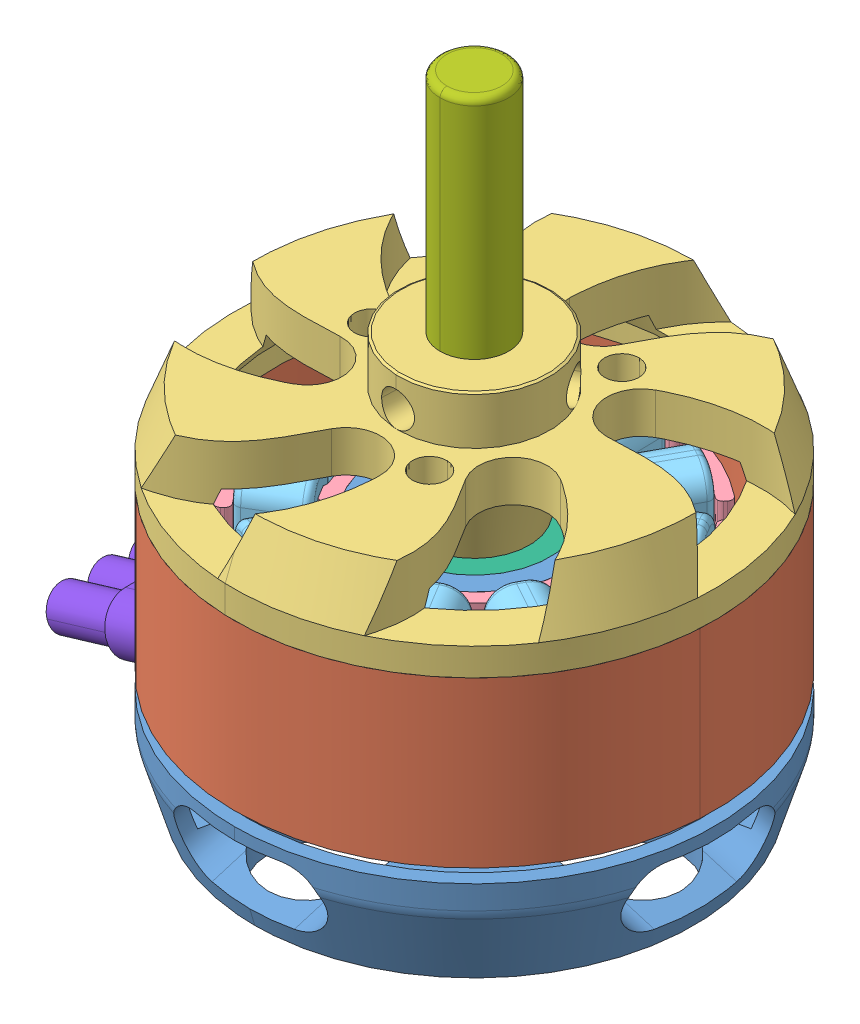
SolidWorks assembly Turnigy Motor, configuration Default. Lengths in mm.
Overall size (45.77 47.68 37.01).
19 component instances, 8 part files, 0 mates.
Components (placement in the parent):
- Bottom Shell.STEP-1: Bottom Shell.STEP [Default] at (12.4509 15.3933 26.7626) size (35.17 18 35)
- Middle Shell.STEP-1: Middle Shell.STEP [Default] at (12.4509 23.3933 26.7626) x (-0.059134 0 0.99825) z (-0.99825 0 -0.059134) size (35 12 35)
- Top Shell.STEP-1: Top Shell.STEP [Default] at (12.4509 35.3933 26.7626) x (0.999258 0 0.038512) z (-0.038512 0 0.999258) size (35.01 11.5 35)
- Inner Coil Rack.STEP-1: Inner Coil Rack.STEP [Default] at (12.4509 25.3933 26.7626) x (0.999766 0 -0.021621) z (0.021621 0 0.999766) size (27 8 27)
- Coil.STEP-1: Coil.STEP [Default] at (12.1274 25.3933 34.9312) x (0.999766 0 -0.021621) z (0.021621 0 0.999766) size (4 11 4.25)
- Coil.STEP-2: Coil.STEP [Default] at (8.0864 25.3933 33.675) x (0.876633 0 0.481159) z (-0.481159 0 0.876633) size (4 11 4.25)
- Coil.STEP-3: Coil.STEP [Default] at (5.2149 25.3933 30.5667) x (0.518607 0 0.855013) z (-0.855013 0 0.518607) size (4 11 4.25)
- Coil.STEP-4: Coil.STEP [Default] at (4.2823 25.3933 26.4391) x (0.021621 0 0.999766) z (-0.999766 0 0.021621) size (4 11 4.25)
- Coil.STEP-5: Coil.STEP [Default] at (5.5384 25.3933 22.3982) x (-0.481159 0 0.876633) z (-0.876633 0 -0.481159) size (4 11 4.25)
- Coil.STEP-6: Coil.STEP [Default] at (8.6467 25.3933 19.5266) x (-0.855013 0 0.518607) z (-0.518607 0 -0.855013) size (4 11 4.25)
- Coil.STEP-7: Coil.STEP [Default] at (12.7743 25.3933 18.594) x (-0.999766 0 0.021621) z (-0.021621 0 -0.999766) size (4 11 4.25)
- Coil.STEP-8: Coil.STEP [Default] at (16.8153 25.3933 19.8501) x (-0.876633 0 -0.481159) z (0.481159 0 -0.876633) size (4 11 4.25)
- Coil.STEP-9: Coil.STEP [Default] at (19.6868 25.3933 22.9584) x (-0.518607 0 -0.855013) z (0.855013 0 -0.518607) size (4 11 4.25)
- Coil.STEP-10: Coil.STEP [Default] at (20.6194 25.3933 27.086) x (-0.021621 0 -0.999766) z (0.999766 0 -0.021621) size (4 11 4.25)
- Coil.STEP-11: Coil.STEP [Default] at (19.3633 25.3933 31.127) x (0.481159 0 -0.876633) z (0.876633 0 0.481159) size (4 11 4.25)
- Coil.STEP-12: Coil.STEP [Default] at (16.255 25.3933 33.9985) x (0.855013 0 -0.518607) z (0.518607 0 0.855013) size (4 11 4.25)
- Inner Bearing.STEP-1: Inner Bearing.STEP [Default] at (12.4509 15.3933 26.7626) size (11 18 11)
- Shaft.STEP-1: Shaft.STEP [Default] at (12.4509 13.8933 26.7626) size (5 47.5 5)
- Wires.STEP-1: Wires.STEP [Default] at (1.5152 18.792 22.2251) x (0 0 1) z (-0.957822 -0.287361 0) size (10 4 16)
